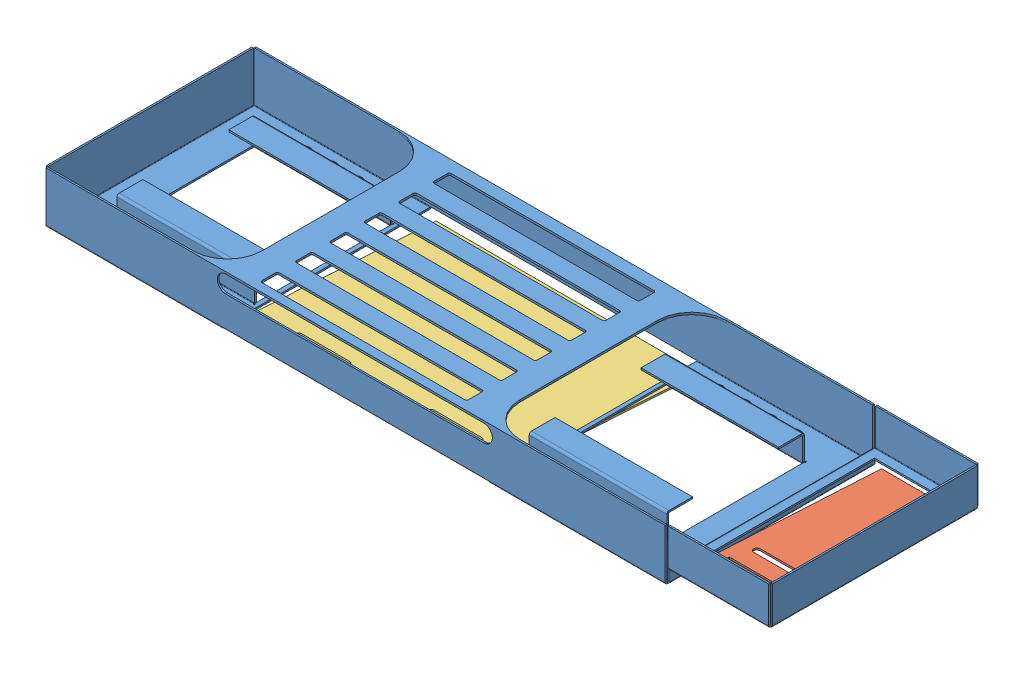
SolidWorks assembly newfangled drive station2, configuration Default. Lengths in mm.
Overall size (1071.88 96 313.07).
3 component instances, 3 part files, 4 mates.
Components (placement in the parent):
- driverstation-1: driverstation [Default] at (258.069 500.7751 872.9739) size (1071.88 76.71 309.88)
- Button Plate-1: Button Plate [Default] at (792.358 511.576 852.6426) x (-1 0 0) z (0 -0.054954 -0.998489) size (118.62 2.54 254)
- Laptop Plate-1: Laptop Plate [Default] at (258.069 491.4139 870.0974) x (-1 0 0) z (0 -0.063842 -0.99796) size (388.62 2.54 311.15)
Mates (geometry in assembly coordinates):
- Coincident1: coincident aligned: line of driverstation-1 through (61.219 501.3461 1025.3551) axis (1 0 0); line of Laptop Plate-1 through (205.999 501.3461 1025.3551) axis (1 0 0)
- Distance1: distance = 2.54 mm: line of Laptop Plate-1 through (63.759 481.4817 714.8398) axis (0 0.063842 0.99796); line of driverstation-1 through (61.219 500.7751 721.3105) axis (0 0 1)
- Coincident3: coincident anti-aligned: line of driverstation-1 through (854.2324 518.5551 979.4507) axis (-1 0 0); line of Button Plate-1 through (838.078 518.5551 979.4507) axis (1 0 0)
- Distance2: distance = 2.54 mm: line of Button Plate-1 through (733.049 504.5968 725.8345) axis (0 0.054954 0.998489); plane of driverstation-1 through (730.509 574.9431 734.0105) normal (1 0 0)
